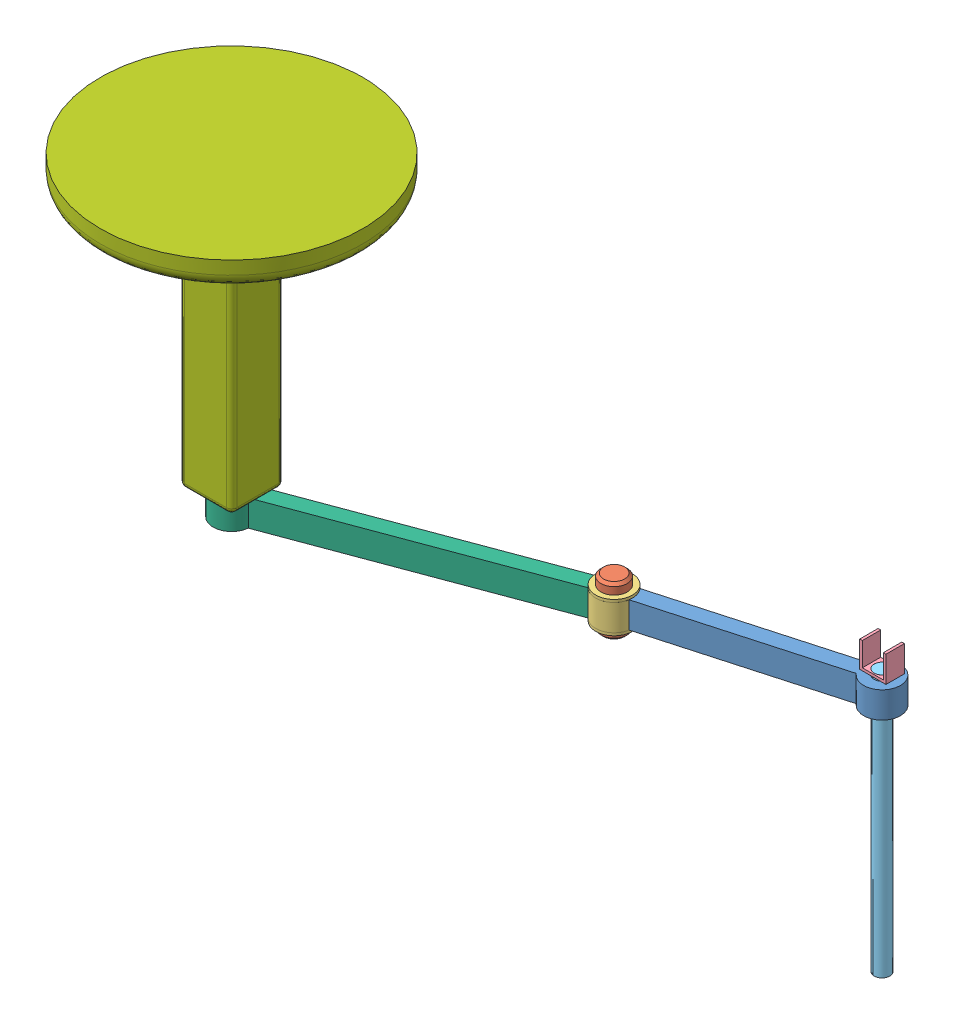
SolidWorks assembly SCARA, configuration Défaut. Lengths in mm.
Overall size (2447.69 2079.05 1203.32).
7 component instances, 7 part files, 13 mates.
Components (placement in the parent):
- axe3-1: axe3 [Défaut] at (316.3715 -402.308 -524.4454) x (0.962764 0 -0.270345) z (0.270345 0 0.962764) size (835.98 100 140)
- LP-1: LP [Défaut] at (-56.9206 -444.2882 -419.6246) x (-0.906781 0 -0.421601) z (0 1 0) size (100 100 190)
- Pièce2-1: Pièce2 [Défaut] at (-56.9206 -362.308 -419.6246) x (0 1 0) z (-0.65708 0 -0.753821) size (120 140.36 140.18)
- pince-1: pince [Défaut] at (792.0088 -291.3614 -606.5751) x (1 0 0.000022) z (0 1 0) size (100 70 100)
- tige_otuil-2: tige_otuil [Défaut] at (742.0096 -1281.3614 -641.5762) x (-0.38469 0 -0.923046) z (0 1 0) size (60 60 1000)
- Axe2-1: Axe2 [Défaut] at (-1119.359 -402.308 -24.5767) x (0.937302 0 -0.348518) z (0.348518 0 0.937302) size (1273.51 100 140)
- Pièce1-1: Pièce1 [Défaut] at (-1119.359 797.692 -24.5767) x (0 -1 0) z (0 0 1) size (1195 1000 1000)
Mates (geometry in assembly coordinates):
- Coaxiale15: concentric: cylinder of Axe2-1 through (-1119.359 -397.308 -24.5767) axis (0 1 0) radius 50; cylinder of Pièce1-1 through (-1119.359 -397.308 -24.5767) axis (0 1 0) radius 50
- Coïncidente13: coincident: plane of Axe2-1 through (-1119.359 -397.308 -24.5767) normal (0 1 0); plane of Pièce1-1 through (-1119.359 -397.308 -24.5767) normal (0 -1 0)
- Coaxiale16: concentric: cylinder of Pièce2-1 through (-56.9206 -292.308 -419.6246) axis (0 -1 0) radius 50; cylinder of Axe2-1 through (-56.9206 -402.308 -419.6246) axis (0 1 0) radius 50
- Coïncidente14: coincident: plane of Pièce2-1 through (-56.9206 -402.308 -419.6246) normal (0 1 0); plane of Axe2-1 through (-1119.359 -402.308 -24.5767) normal (0 -1 0)
- Coaxiale20: concentric: cylinder of LP-1 through (-56.9206 -254.2882 -419.6246) axis (0 -1 0) radius 50; cylinder of Pièce2-1 through (-56.9206 -292.308 -419.6246) axis (0 -1 0) radius 50
- Verrouiller1: lock: unknown of axe3-1; unknown of LP-1
- Coaxiale21: concentric: cylinder of axe3-1 through (742.0096 -402.308 -641.5762) axis (0 1 0) radius 30; cylinder of tige_otuil-2 through (742.0096 -281.3614 -641.5762) axis (0 -1 0) radius 30
- Coïncidente21: coincident: circle of pince-1; circle of tige_otuil-2
- DistanceLimite1: limit distance = 10.9466 mm: plane of pince-1 through (792.0088 -291.3614 -606.5751) normal (0 -1 0); plane of axe3-1 through (316.3715 -302.308 -524.4454) normal (0 1 0)
- DistanceLimite2: limit distance = 879.0534 mm: plane of axe3-1 through (316.3715 -402.308 -524.4454) normal (0 -1 0); plane of tige_otuil-2 through (742.0096 -1281.3614 -641.5762) normal (0 -1 0)
- DistanceLimite3: limit distance = 128.7678 mm: line of axe3-1 through (-4.2099 -302.308 -465.6853) axis (0 -1 0); line of Axe2-1 through (-126.647 -302.308 -425.8068) axis (0 -1 0)
- Coïncidente26: coincident: plane of axe3-1 through (308.2353 -302.308 -553.4203) normal (-0.270345 0 -0.962764); line of Pièce2-1 through (-4.0158 -302.308 -465.7398) axis (0 -1 0)
- Coïncidente27: coincident: plane of axe3-1 through (316.3715 -402.308 -524.4454) normal (0 -1 0); circle of Axe2-1
